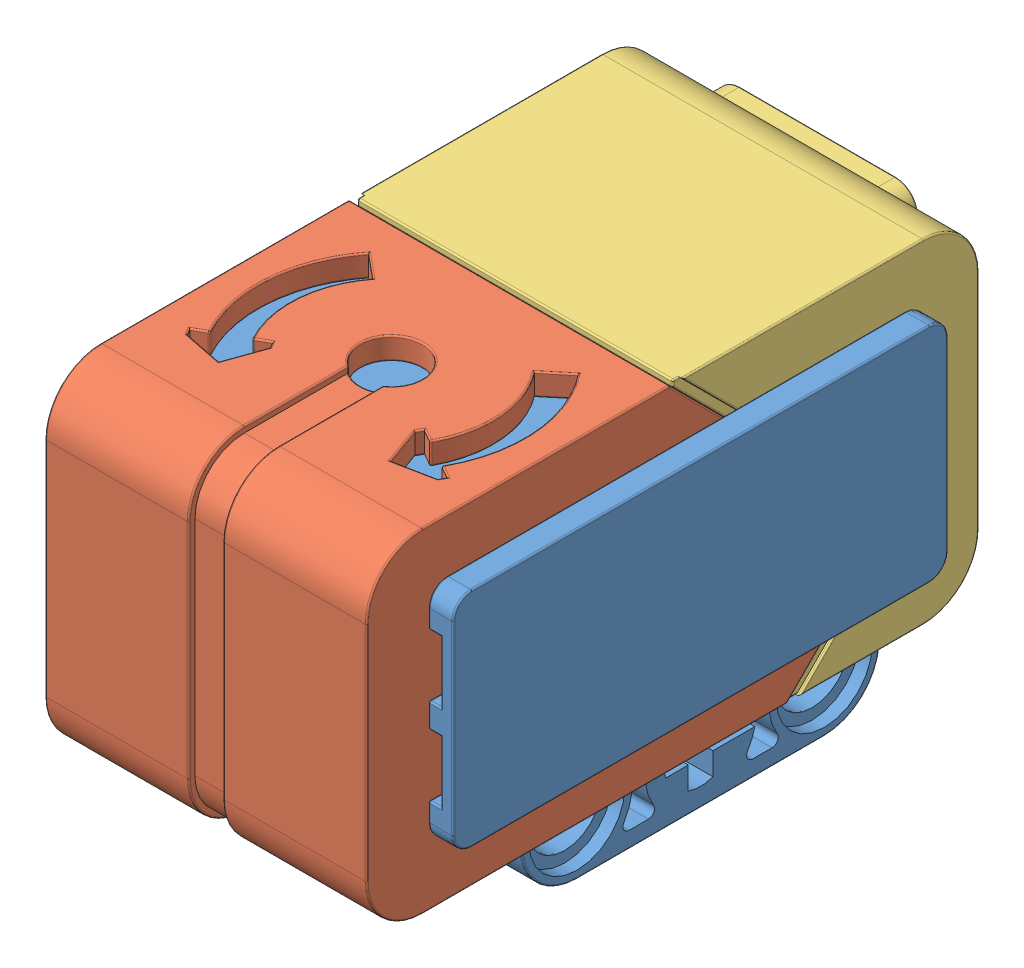
SolidWorks assembly 95380, configuration Default. Lengths in mm.
Overall size (24 31.04 39.62).
5 component instances, 4 part files, 0 mates.
Components (placement in the parent):
- 99380.stp-1: 99380.stp [Default] at origin size (24 31.04 39.62)
  - 99377p01-LtBluishGray.stp-1: 99377p01-LtBluishGray.stp [Default] at origin size (24 29.6 38)
  - 99397-LtBluishGray.stp-1: 99397-LtBluishGray.stp [Default] at (0 0.44 13.8) size (22.4 21.6 30.66)
  - 99376-White.stp-1: 99376-White.stp [Default] at (0 0.44 -14.2) size (22.3 23.6 19.62)
  - 54732b-LtBluishGray.stp-1: 54732b-LtBluishGray.stp [Default] at (0 2.04 -20.2) x (-1 0 0) z (0 0 -1) size (12 14.56 14.4)
